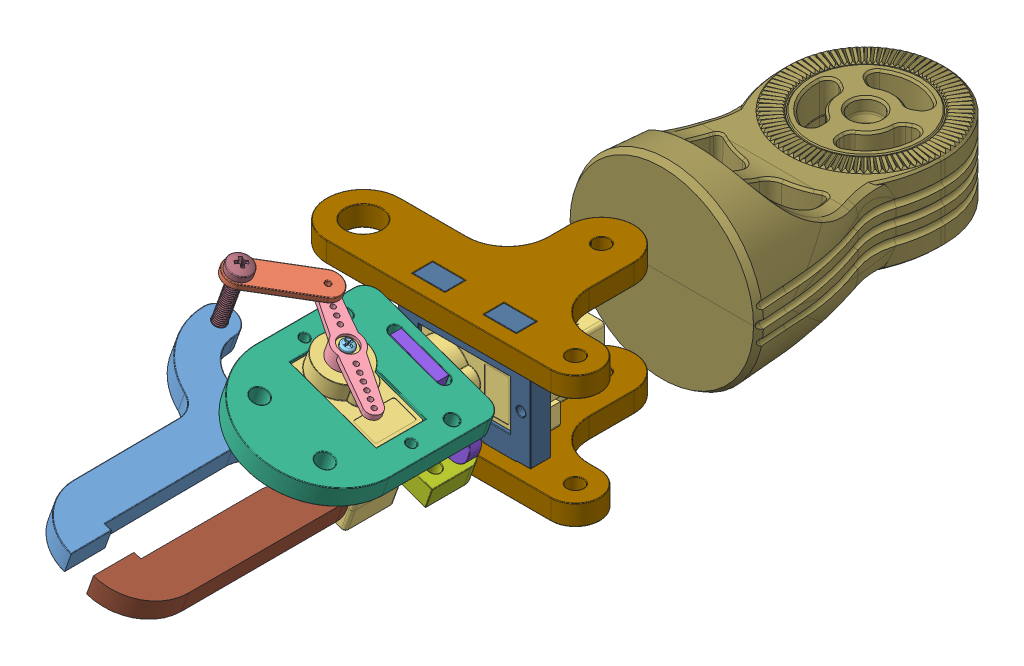
SolidWorks assembly Assembly T307, configuration Domyślna. Lengths in mm.
Overall size (70 52.87 206.53).
19 component instances, 13 part files, 29 mates.
Components (placement in the parent):
- Part2 T307-1: Part2 T307 [Domyślna] at (-12.6426 4.2933 42.6146) x (-0.336036 -0.941849 0) z (0.941828 -0.336028 -0.006711) size (5.03 63.65 32.05)
- Part9 T307-1: Part9 T307 [Domyślna] at (-19.9754 23.4452 27.176) x (-0.633165 0.225903 0.740318) z (0.336036 0.941849 0) size (22.5 6.5 1.5)
- SG90 - Micro Servo 9g - Tower Pro-2: SG90 - Micro Servo 9g - Tower Pro [Braço Duplo] at (-18.3131 -17.0351 -1.3332) x (0.941849 -0.336036 0) z (0 0 1) size (37.23 30.93 19.67) (flexible)
  - SG90 - Micro Servo 9g - Tower Pro.1-1: SG90 - Micro Servo 9g - Tower Pro.1 [Peça] at (6.6733 16.8178 27.7832) size (32.1 29.95 12.4)
  - SG90 - Micro Servo 9g - Tower Pro.3-1: SG90 - Micro Servo 9g - Tower Pro.3 [Peça] at (1.5233 36.8178 27.7832) x (0.908727 0 0.41739) z (-0.41739 0 0.908727) size (32.1 3.8 6.9)
  - SG90 - Micro Servo 9g - Tower Pro.6-1: SG90 - Micro Servo 9g - Tower Pro.6 [BS EN ISO 7045 - M2 x 4 - Z - 4S] at (1.5233 37.1178 27.7832) x (0 -1 0) z (0 0 1) size (5.28 3.1 3.1)
- Part4 T307-1: Part4 T307 [Domyślna] at (-3.8059 3.7674 26.45) x (-0.941849 0.336036 0) z (0.336036 0.941849 0) size (35 45 5)
- Part5 T307-1: Part5 T307 [Domyślna] at (-8.1743 -8.4766 26.45) x (-0.941849 0.336036 0) z (0.336036 0.941849 0) size (35 13 5)
- Part8 T307-1: Part8 T307 [Domyślna] at (-5.15 0 11.35) x (0.941849 -0.336036 0) z (0 0 1) size (35 18 3)
- SG90 - Micro Servo 9g - Tower Pro-1: SG90 - Micro Servo 9g - Tower Pro [Braço Duplo] at (-6.6733 27.7832 -26.9678) x (1 0 0) z (0 -1 0) size (37.48 30.93 17.29) (flexible)
  - SG90 - Micro Servo 9g - Tower Pro.1-1: SG90 - Micro Servo 9g - Tower Pro.1 [Peça] at (6.6733 16.8178 27.7832) size (32.1 29.95 12.4)
  - SG90 - Micro Servo 9g - Tower Pro.3-1: SG90 - Micro Servo 9g - Tower Pro.3 [Peça] at (1.5233 36.8178 27.7832) x (-0.941849 0 -0.336036) z (0.336036 0 -0.941849) size (32.1 3.8 6.9)
  - SG90 - Micro Servo 9g - Tower Pro.6-1: SG90 - Micro Servo 9g - Tower Pro.6 [BS EN ISO 7045 - M2 x 4 - Z - 4S] at (1.5233 37.1178 27.7832) x (0 -1 0) z (0 0 1) size (5.28 3.1 3.1)
- Part6 T307-1: Part6 T307 [Domyślna] at (-2.75 -13.6 6) x (-1 0 0) z (0 -1 0) size (70 41 5)
- Part6 T307-2: Part6 T307 [Domyślna] at (-2.75 13.6 6) x (-1 0 0) z (0 -1 0) size (70 41 5)
- Part7 T307-1: Part7 T307 [Domyślna] at origin size (32.5 32.2 5)
- Part T307-1: Part T307 [Domyślna] at (2.1809 -4.7526 42.5438) x (-0.336036 -0.941849 0) z (0.941849 -0.336036 -0.000722) size (5 59.62 16.16)
- 5.1.3 Stamp-1: 5.1.3 Stamp [Domyślna] at (1.7336 0 -94.2237) x (0 -1 0) z (0 0 -1) size (46.78 47.15 69.53)
- pan head cross recess screw_iso-4: pan head cross recess screw_iso [ISO 7045 - M3 x 25 - Z - 25S] at (-23.9822 28.2193 33.0986) x (-0.336036 -0.941849 0) z (-0.508718 0.181502 0.841583) size (27.35 5.6 5.6)
Mates (geometry in assembly coordinates):
- Wspólnie2: coincident anti-aligned: plane of Part7 T307-1 through (0 -11.1 2.5) normal (0 -1 0); plane of Part6 T307-1 through (24.75 -11.1 0) normal (0 1 0)
- Wspólnie3: coincident anti-aligned: plane of Part7 T307-1 through (0 0 -2.5) normal (0 0 -1); plane of Part6 T307-1 through (12.75 -16.1 -2.5) normal (0 0 1)
- Wspólnie4: coincident anti-aligned: plane of Part7 T307-1 through (-12.75 0 2.5) normal (-1 0 0); plane of Part6 T307-1 through (-12.75 -16.1 2.5) normal (1 0 0)
- Wspólnie61: coincident anti-aligned: plane of Part7 T307-1 through (0 0 -2.5) normal (0 0 -1); plane of SG90 - Micro Servo 9g - Tower Pro-1/SG90 - Micro Servo 9g - Tower Pro.1-1 through (-15.2 -5.25 -2.5) normal (0 0 1)
- Koncentryczne1: concentric anti-aligned: cylinder of Part7 T307-1 through (13.9 0 2.5) axis (0 0 -1) radius 1.1; cylinder of SG90 - Micro Servo 9g - Tower Pro-1/SG90 - Micro Servo 9g - Tower Pro.1-1 through (13.9 0 -20.7) axis (0 0 1) radius 1.1
- Koncentryczne2: concentric anti-aligned: cylinder of Part7 T307-1 through (-13.9 0 2.5) axis (0 0 -1) radius 1.1; cylinder of SG90 - Micro Servo 9g - Tower Pro-1/SG90 - Micro Servo 9g - Tower Pro.1-1 through (-13.9 0 -20.7) axis (0 0 1) radius 1.1
- Wspólnie62: coincident anti-aligned: plane of SG90 - Micro Servo 9g - Tower Pro-1/SG90 - Micro Servo 9g - Tower Pro.3-1 through (-5.15 0 9.85) normal (0 0 1); plane of Part8 T307-1 through (8.2039 -4.2336 9.85) normal (0 0 -1)
- Koncentryczne3: concentric aligned: cylinder of SG90 - Micro Servo 9g - Tower Pro-1/SG90 - Micro Servo 9g - Tower Pro.3-1 through (8.4597 -4.8557 9.85) axis (0 0 1) radius 0.6; cylinder of Part8 T307-1 through (8.4597 -4.8557 9.85) axis (0 0 1) radius 0.6
- Koncentryczne4: concentric aligned: cylinder of SG90 - Micro Servo 9g - Tower Pro-1/SG90 - Micro Servo 9g - Tower Pro.3-1 through (-18.7597 4.8557 9.85) axis (0 0 1) radius 0.6; cylinder of Part8 T307-1 through (-18.7597 4.8557 9.85) axis (0 0 1) radius 0.6
- Wspólnie64: coincident aligned: plane of Part8 T307-1 through (-7.9416 10.5517 12.85) normal (0.336036 0.941849 0); plane of Part4 T307-1 through (-2.1257 8.4766 34.8426) normal (0.336036 0.941849 0)
- Wspólnie65: coincident anti-aligned: plane of Part8 T307-1 through (8.2039 -4.2336 12.85) normal (0 0 1); plane of Part4 T307-1 through (3.7138 6.3932 12.85) normal (0 0 -1)
- Szerokość2: width aligned: plane of Part4 T307-1 through (8.4701 4.6962 20.35) normal (-0.941849 0.336036 0); plane of Part4 T307-1 through (-12.7215 12.257 20.35) normal (0.941849 -0.336036 0); plane of Part8 T307-1 through (-9.6218 5.8424 12.85) normal (-0.941849 0.336036 0); plane of Part8 T307-1 through (3.6902 6.4016 12.85) normal (0.941849 -0.336036 0)
- Wspólnie69: coincident anti-aligned: plane of Part8 T307-1 through (6.6917 -8.4719 12.85) normal (-0.336036 -0.941849 0); plane of Part5 T307-1 through (-6.4941 -3.7674 34.8426) normal (0.336036 0.941849 0)
- Wspólnie70: coincident aligned: plane of Part5 T307-1 through (9.9882 -9.648 35.35) normal (0.941849 -0.336036 0); plane of Part4 T307-1 through (14.3567 2.596 35.35) normal (0.941849 -0.336036 0)
- Wspólnie72: coincident anti-aligned: plane of Part8 T307-1 through (8.2039 -4.2336 12.85) normal (0 0 1); plane of Part5 T307-1 through (-0.6547 -5.8508 12.85) normal (0 0 -1)
- Wspólnie74: coincident anti-aligned: plane of Part4 T307-1 through (-3.8059 3.7674 34.8426) normal (-0.336036 -0.941849 0); plane of SG90 - Micro Servo 9g - Tower Pro-2/SG90 - Micro Servo 9g - Tower Pro.1-1 through (-18.122 8.8751 31.7) normal (0.336036 0.941849 0)
- Koncentryczne5: concentric anti-aligned: cylinder of Part4 T307-1 through (-15.2174 13.1475 26.45) axis (-0.336036 -0.941849 0) radius 1.1; cylinder of SG90 - Micro Servo 9g - Tower Pro-2/SG90 - Micro Servo 9g - Tower Pro.1-1 through (-23.0134 -8.7034 26.45) axis (0.336036 0.941849 0) radius 1.1
- Koncentryczne6: concentric anti-aligned: cylinder of Part4 T307-1 through (10.966 3.8057 26.45) axis (-0.336036 -0.941849 0) radius 1.1; cylinder of SG90 - Micro Servo 9g - Tower Pro-2/SG90 - Micro Servo 9g - Tower Pro.1-1 through (3.17 -18.0452 26.45) axis (0.336036 0.941849 0) radius 1.1
- Wspólnie75: coincident anti-aligned: plane of SG90 - Micro Servo 9g - Tower Pro-2/SG90 - Micro Servo 9g - Tower Pro.3-1 through (-4.5063 17.1298 26.45) normal (0.336036 0.941849 0); plane of Part9 T307-1 through (-15.1621 20.9316 21.2535) normal (-0.336036 -0.941849 0)
- Koncentryczne7: concentric anti-aligned: cylinder of SG90 - Micro Servo 9g - Tower Pro-2/SG90 - Micro Servo 9g - Tower Pro.3-1 through (-15.1621 20.9316 21.2535) axis (0.336036 0.941849 0) radius 0.6; cylinder of Part9 T307-1 through (-14.658 22.3444 21.2535) axis (-0.336036 -0.941849 0) radius 0.6
- Wspólnie77: coincident anti-aligned: plane of Part9 T307-1 through (-14.658 22.3444 21.2535) normal (0.336036 0.941849 0); plane of pan head cross recess screw_iso-4 through (-23.5997 25.5346 33.9088) normal (-0.336036 -0.941849 0)
- Koncentryczne10: concentric anti-aligned: cylinder of Part9 T307-1 through (-24.7887 25.9588 33.0986) axis (-0.336036 -0.941849 0) radius 1.5; cylinder of pan head cross recess screw_iso-4 through (-15.4469 52.1422 33.0986) axis (0.336036 0.941849 0) radius 2.8
- Koncentryczne12: concentric anti-aligned: cylinder of pan head cross recess screw_iso-4 through (-15.4469 52.1422 33.0986) axis (0.336036 0.941849 0) radius 1.5; cylinder of Part2 T307-1 through (-20.4076 38.2382 33.0986) axis (-0.336036 -0.941849 0) radius 1.5
- Wspólnie78: coincident anti-aligned: plane of Part4 T307-1 through (-3.8059 3.7674 34.8426) normal (-0.336036 -0.941849 0); plane of Part2 T307-1 through (-11.8116 6.6237 42.55) normal (0.336036 0.941849 0)
- Koncentryczne13: concentric anti-aligned: cylinder of Part4 T307-1 through (-10.1314 11.3329 42.55) axis (-0.336036 -0.941849 0) radius 2; cylinder of Part2 T307-1 through (-28.6134 -40.4688 42.55) axis (0.336036 0.941849 0) radius 3.5
- Wspólnie80: coincident anti-aligned: plane of Part4 T307-1 through (-3.8059 3.7674 34.8426) normal (-0.336036 -0.941849 0); plane of Part T307-1 through (4.1999 0.9111 42.55) normal (0.336036 0.941849 0)
- Koncentryczne14: concentric anti-aligned: cylinder of Part4 T307-1 through (5.88 5.6203 42.55) axis (-0.336036 -0.941849 0) radius 2; cylinder of Part T307-1 through (-12.602 -46.1814 42.55) axis (0.336036 0.941849 0) radius 3.5
- Równolegle1: parallel aligned: plane of 5.1.3 Stamp-1 through (1.7336 0 -44.2237) normal (0 0 1); plane of assembly through (0 0 0) normal (0 0 1)
- Wspólnie82: coincident: line of 5.1.3 Stamp-1 through (24.2336 0 -44.2237) axis (-1 0 0); plane of assembly
